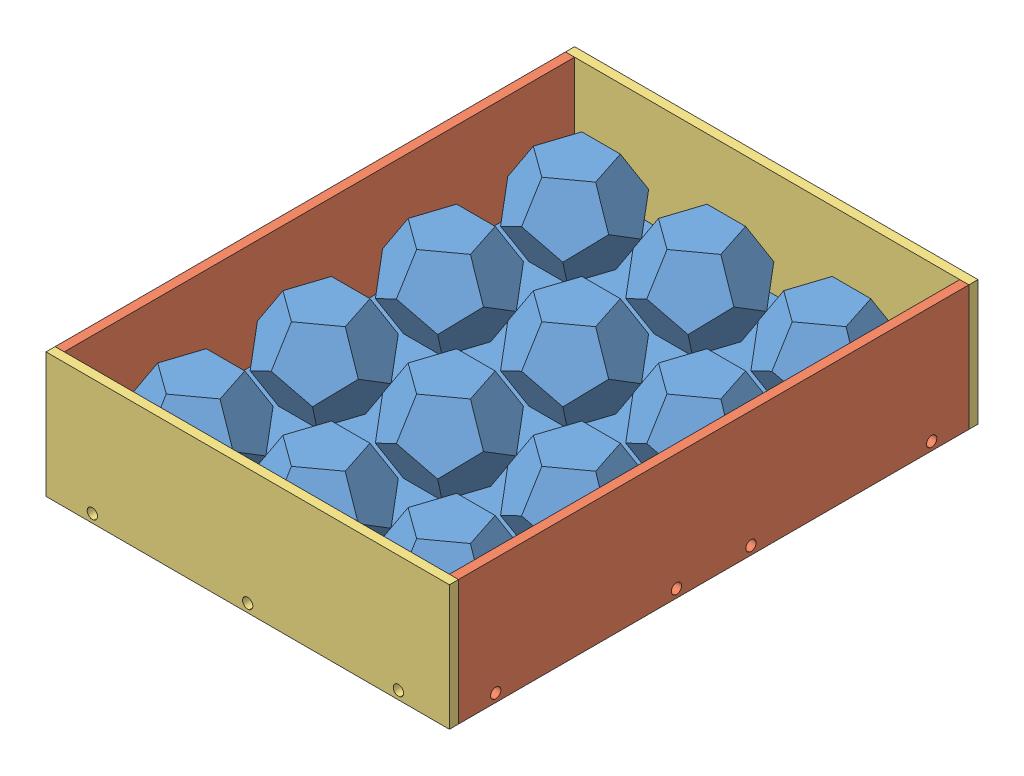
SolidWorks assembly 12 Part Mold, configuration Default. Lengths in mm.
Overall size (133 41.27 174.27).
5 component instances, 3 part files, 0 mates.
Components (placement in the parent):
- 12 Section Mold-1: 12 Section Mold [Default] at origin size (127 34.63 168.28)
- 4 Wall^12 Part Mold-1: 4 Wall^12 Part Mold [Default] at origin size (3 41.27 168.28) (virtual)
- 3 Wall^12 Part Mold-1: 3 Wall^12 Part Mold [Default] at origin size (133 41.27 3) (virtual)
- 4 Wall^12 Part Mold-2: 4 Wall^12 Part Mold [Default] at (82.55 0 123.825) x (-1 0 0) z (0 0 -1) size (3 41.27 168.28) (virtual)
- 3 Wall^12 Part Mold-2: 3 Wall^12 Part Mold [Default] at (0 0 -171.275) size (133 41.27 3) (virtual)
